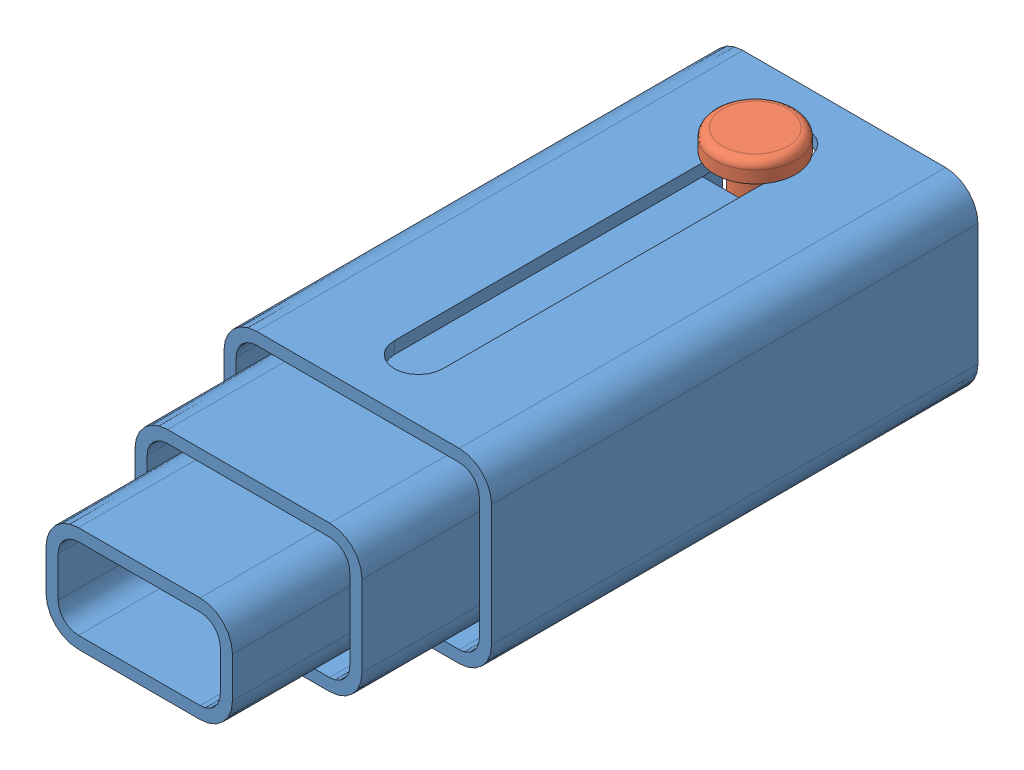
SolidWorks assembly Scoperino, configuration Default. Lengths in mm.
Overall size (66 60 173.91).
4 component instances, 2 part files, 9 mates.
Components (placement in the parent):
- Telescope-1: Telescope [Large] at (46.4632 61.0226 92.3158) size (66 46 120)
- Telescope-2: Telescope [Medium] at (46.4632 61.0226 119.2732) size (56 36 120)
- Telescope-3: Telescope [Small] at (46.4632 61.0226 146.2306) size (46 26 120)
- Pin-1: Pin [Default] at (46.4632 61.0226 54.2732) x (0.758493 0 0.651681) z (0 1 0) size (20 20 60)
Mates (geometry in assembly coordinates):
- Width1: width aligned: plane of Telescope-1 through (21.4632 81.0226 152.3158) normal (0 -1 0); plane of Telescope-1 through (21.4632 41.0226 152.3158) normal (0 1 0); plane of Telescope-2 through (66.4632 79.0226 179.2732) normal (0 1 0); plane of Telescope-2 through (66.4632 43.0226 179.2732) normal (0 -1 0)
- Width2: width aligned: plane of Telescope-1 through (16.4632 46.0226 152.3158) normal (1 0 0); plane of Telescope-1 through (76.4632 46.0226 152.3158) normal (-1 0 0); plane of Telescope-2 through (74.4632 71.0226 179.2732) normal (1 0 0); plane of Telescope-2 through (18.4632 71.0226 179.2732) normal (-1 0 0)
- Width3: width anti-aligned: plane of Telescope-2 through (21.4632 51.0226 179.2732) normal (1 0 0); plane of Telescope-2 through (71.4632 51.0226 179.2732) normal (-1 0 0); plane of Telescope-3 through (23.4632 66.0226 206.2306) normal (-1 0 0); plane of Telescope-3 through (69.4632 66.0226 206.2306) normal (1 0 0)
- Width4: width anti-aligned: plane of Telescope-2 through (26.4632 76.0226 179.2732) normal (0 -1 0); plane of Telescope-2 through (26.4632 46.0226 179.2732) normal (0 1 0); plane of Telescope-3 through (61.4632 74.0226 206.2306) normal (0 1 0); plane of Telescope-3 through (61.4632 48.0226 206.2306) normal (0 -1 0)
- Linear/Linear Coupler1: linear coupler = 1 : 2 mm: plane of Telescope-2 through (66.4632 71.0226 179.2732) normal (0 0 1); plane of Telescope-3 through (61.4632 66.0226 206.2306) normal (0 0 1)
- Slot1: slot anti-aligned: cylinder of Telescope-1 through (46.4632 38.0226 47.3158) axis (0 1 0) radius 6; cylinder of Pin-1 through (46.4632 86.0226 54.2732) axis (0 -1 0) radius 5; cylinder of Telescope-1 through (46.4632 38.0226 137.3158) axis (0 1 0) radius 6
- Width5: width anti-aligned: plane of Pin-1 through (46.4632 86.0226 54.2732) normal (0 -1 0); plane of Telescope-1 through (46.4632 36.0226 54.2732) normal (0 1 0); plane of Pin-1 through (71.4632 84.0226 152.3158) normal (0 1 0); plane of Telescope-1 through (71.4632 38.0226 152.3158) normal (0 -1 0)
- Slot2: slot anti-aligned: cylinder of Pin-1 through (46.4632 86.0226 54.2732) axis (0 -1 0) radius 5; plane of Telescope-1 through (52.4632 38.0226 47.3158) normal (-1 0 0); cylinder of Telescope-1 through (46.4632 38.0226 47.3158) axis (0 1 0) radius 6
- Tangent2: tangent anti-aligned: plane of Telescope-2 through (66.4632 71.0226 59.2732) normal (0 0 -1); cylinder of Pin-1 through (46.4632 86.0226 54.2732) axis (0 -1 0) radius 5
